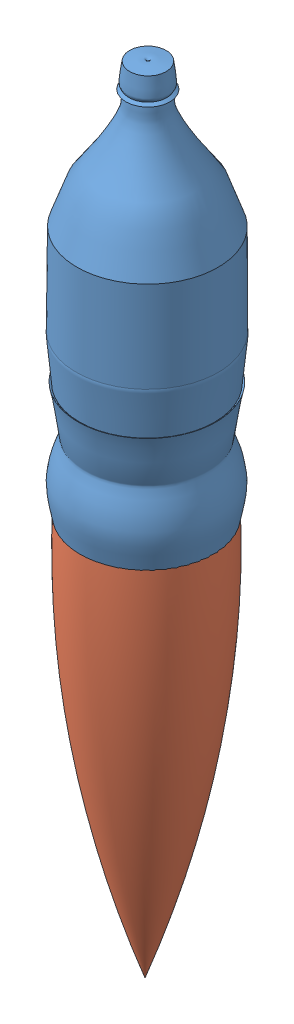
SolidWorks assembly Assem1, configuration Default. Lengths in mm.
Overall size (147.6 555.24 138.53).
2 component instances, 2 part files, 1 mates.
Components (placement in the parent):
- 2l-coke-bottle-1: 2l-coke-bottle [Default] at (-176.3857 -133.055 42.9303) size (99.44 302.08 99.09)
- nosecone-1: nosecone [Default] at (-113.7376 -257.5358 42.9303) x (0.040611 0.999138 -0.008548) z (0.225272 -0.000821 0.974296) size (287.29 113.38 113.47)
Mates (geometry in assembly coordinates):
- Concentric1: concentric anti-aligned: circle of 2l-coke-bottle-1; circle of nosecone-1
